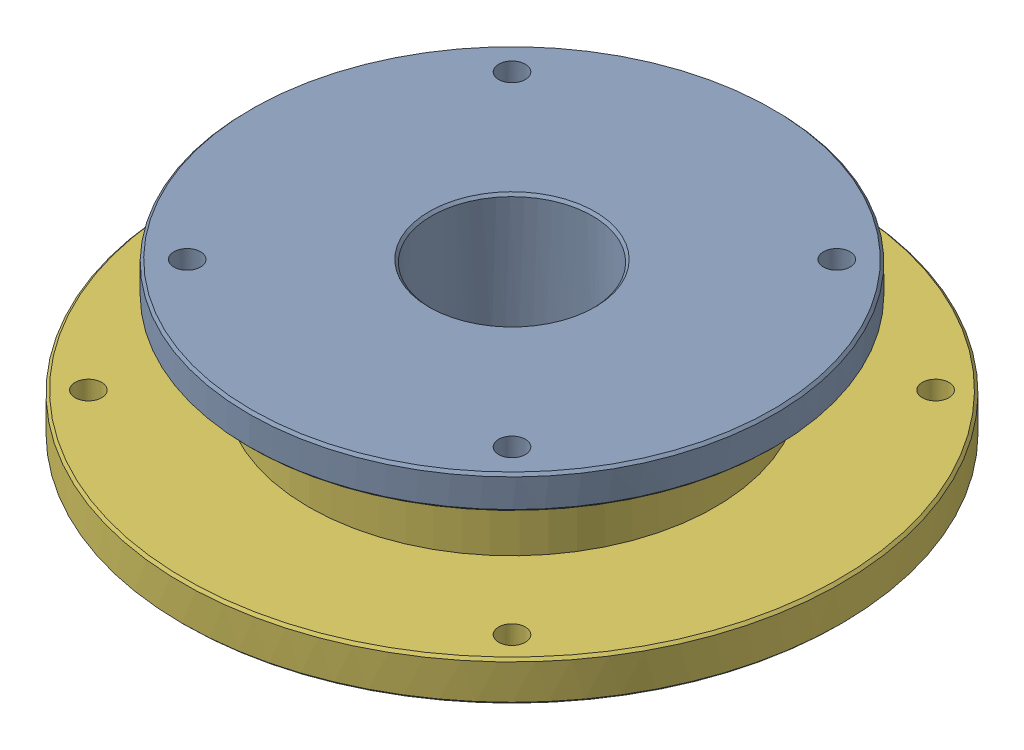
SolidWorks assembly 22212 Bearing Flange Assembly, configuration Default. Lengths in mm.
Overall size (198 46 198).
43 component instances, 6 part files, 6 mates.
Components (placement in the parent):
- 22212 bearing flange-1: 22212 bearing flange [Default] at (0 40.4807 0) size (158 40 158)
- SKF_22212 E_oh-1: SKF_22212 E_oh [Default] at (0 6 0) x (0 1 0) z (-0.933971 0 -0.357349) size (28 110 110)
  - SKF_22212 E_ir_oh-1: SKF_22212 E_ir_oh [Default] at origin size (28 75.82 75.82)
  - SKF_22212 E_or_oh-1: SKF_22212 E_or_oh [Default] at origin size (28 110 110)
  - SKF_22212 E_r1_oh-1: SKF_22212 E_r1_oh [Default] at origin size (11.89 13.47 12.6)
  - SKF_22212 E_r2_oh-1: SKF_22212 E_r2_oh [Default] at origin size (11.89 13.47 12.6)
  - SKF_22212 E_r1_oh-2: SKF_22212 E_r1_oh [Default] x (1 0 0) z (0 -0.324699 0.945817) size (11.89 13.47 12.6)
  - SKF_22212 E_r2_oh-2: SKF_22212 E_r2_oh [Default] x (1 0 0) z (0 -0.324699 0.945817) size (11.89 13.47 12.6)
  - SKF_22212 E_r1_oh-3: SKF_22212 E_r1_oh [Default] x (1 0 0) z (0 -0.614213 0.789141) size (11.89 13.47 12.6)
  - SKF_22212 E_r2_oh-3: SKF_22212 E_r2_oh [Default] x (1 0 0) z (0 -0.614213 0.789141) size (11.89 13.47 12.6)
  - SKF_22212 E_r1_oh-4: SKF_22212 E_r1_oh [Default] x (1 0 0) z (0 -0.837166 0.546948) size (11.89 13.47 12.6)
  - SKF_22212 E_r2_oh-4: SKF_22212 E_r2_oh [Default] x (1 0 0) z (0 -0.837166 0.546948) size (11.89 13.47 12.6)
  - SKF_22212 E_r1_oh-5: SKF_22212 E_r1_oh [Default] x (1 0 0) z (0 -0.9694 0.245485) size (11.89 13.47 12.6)
  - SKF_22212 E_r2_oh-5: SKF_22212 E_r2_oh [Default] x (1 0 0) z (0 -0.9694 0.245485) size (11.89 13.47 12.6)
  - SKF_22212 E_r1_oh-6: SKF_22212 E_r1_oh [Default] x (1 0 0) z (0 -0.996584 -0.082579) size (11.89 13.47 12.6)
  - SKF_22212 E_r2_oh-6: SKF_22212 E_r2_oh [Default] x (1 0 0) z (0 -0.996584 -0.082579) size (11.89 13.47 12.6)
  - SKF_22212 E_r1_oh-7: SKF_22212 E_r1_oh [Default] x (1 0 0) z (0 -0.915773 -0.401695) size (11.89 13.47 12.6)
  - SKF_22212 E_r2_oh-7: SKF_22212 E_r2_oh [Default] x (1 0 0) z (0 -0.915773 -0.401695) size (11.89 13.47 12.6)
  - SKF_22212 E_r1_oh-8: SKF_22212 E_r1_oh [Default] x (1 0 0) z (0 -0.735724 -0.677282) size (11.89 13.47 12.6)
  - SKF_22212 E_r2_oh-8: SKF_22212 E_r2_oh [Default] x (1 0 0) z (0 -0.735724 -0.677282) size (11.89 13.47 12.6)
  - SKF_22212 E_r1_oh-9: SKF_22212 E_r1_oh [Default] x (1 0 0) z (0 -0.475947 -0.879474) size (11.89 13.47 12.6)
  - SKF_22212 E_r2_oh-9: SKF_22212 E_r2_oh [Default] x (1 0 0) z (0 -0.475947 -0.879474) size (11.89 13.47 12.6)
  - SKF_22212 E_r1_oh-10: SKF_22212 E_r1_oh [Default] x (1 0 0) z (0 -0.164595 -0.986361) size (11.89 13.47 12.6)
  - SKF_22212 E_r2_oh-10: SKF_22212 E_r2_oh [Default] x (1 0 0) z (0 -0.164595 -0.986361) size (11.89 13.47 12.6)
  - SKF_22212 E_r1_oh-11: SKF_22212 E_r1_oh [Default] x (1 0 0) z (0 0.164595 -0.986361) size (11.89 13.47 12.6)
  - SKF_22212 E_r2_oh-11: SKF_22212 E_r2_oh [Default] x (1 0 0) z (0 0.164595 -0.986361) size (11.89 13.47 12.6)
  - SKF_22212 E_r1_oh-12: SKF_22212 E_r1_oh [Default] x (1 0 0) z (0 0.475947 -0.879474) size (11.89 13.47 12.6)
  - SKF_22212 E_r2_oh-12: SKF_22212 E_r2_oh [Default] x (1 0 0) z (0 0.475947 -0.879474) size (11.89 13.47 12.6)
  - SKF_22212 E_r1_oh-13: SKF_22212 E_r1_oh [Default] x (1 0 0) z (0 0.735724 -0.677282) size (11.89 13.47 12.6)
  - SKF_22212 E_r2_oh-13: SKF_22212 E_r2_oh [Default] x (1 0 0) z (0 0.735724 -0.677282) size (11.89 13.47 12.6)
  - SKF_22212 E_r1_oh-14: SKF_22212 E_r1_oh [Default] x (1 0 0) z (0 0.915773 -0.401695) size (11.89 13.47 12.6)
  - SKF_22212 E_r2_oh-14: SKF_22212 E_r2_oh [Default] x (1 0 0) z (0 0.915773 -0.401695) size (11.89 13.47 12.6)
  - SKF_22212 E_r1_oh-15: SKF_22212 E_r1_oh [Default] x (1 0 0) z (0 0.996584 -0.082579) size (11.89 13.47 12.6)
  - SKF_22212 E_r2_oh-15: SKF_22212 E_r2_oh [Default] x (1 0 0) z (0 0.996584 -0.082579) size (11.89 13.47 12.6)
  - SKF_22212 E_r1_oh-16: SKF_22212 E_r1_oh [Default] x (1 0 0) z (0 0.9694 0.245485) size (11.89 13.47 12.6)
  - SKF_22212 E_r2_oh-16: SKF_22212 E_r2_oh [Default] x (1 0 0) z (0 0.9694 0.245485) size (11.89 13.47 12.6)
  - SKF_22212 E_r1_oh-17: SKF_22212 E_r1_oh [Default] x (1 0 0) z (0 0.837166 0.546948) size (11.89 13.47 12.6)
  - SKF_22212 E_r2_oh-17: SKF_22212 E_r2_oh [Default] x (1 0 0) z (0 0.837166 0.546948) size (11.89 13.47 12.6)
  - SKF_22212 E_r1_oh-18: SKF_22212 E_r1_oh [Default] x (1 0 0) z (0 0.614213 0.789141) size (11.89 13.47 12.6)
  - SKF_22212 E_r2_oh-18: SKF_22212 E_r2_oh [Default] x (1 0 0) z (0 0.614213 0.789141) size (11.89 13.47 12.6)
  - SKF_22212 E_r1_oh-19: SKF_22212 E_r1_oh [Default] x (1 0 0) z (0 0.324699 0.945817) size (11.89 13.47 12.6)
  - SKF_22212 E_r2_oh-19: SKF_22212 E_r2_oh [Default] x (1 0 0) z (0 0.324699 0.945817) size (11.89 13.47 12.6)
- 22212 bearing bottom flange-1: 22212 bearing bottom flange [Default] at origin size (198 34 198)
Mates (geometry in assembly coordinates):
- Concentric1: concentric anti-aligned: cylinder of mat bich bac dan 22212-1 through (0 40.4807 0) axis (0 1 0) radius 30; cylinder of SKF_22212 E-1/SKF_22212 E_ir-1 through (0 34 0) axis (0 -1 0) radius 30
- Coincident1: coincident anti-aligned: plane of mat bich bac dan 22212-1 through (-30 34 0) normal (0 -1 0); plane of SKF_22212 E-1/SKF_22212 E_ir-1 through (11.2565 34 -29.4201) normal (0 1 0)
- Concentric2: concentric aligned: cylinder of SKF_22212 E-1/SKF_22212 E_or-1 through (0 34 0) axis (0 -1 0) radius 55; cylinder of mat bich bac dan 22212 duoi-1 through (0 0 0) axis (0 -1 0) radius 55
- Coincident2: coincident anti-aligned: plane of SKF_22212 E-1/SKF_22212 E_or-1 through (19.1182 6 -49.9674) normal (0 -1 0); plane of mat bich bac dan 22212 duoi-1 through (-50 6 0) normal (0 1 0)
- Coincident3: coordinate: unknown of mat bich bac dan 22212 duoi-1
- Coincident4: coincident aligned: plane of mat bich bac dan 22212-1 through (0 40.4807 0) normal (0 0 1); plane of mat bich bac dan 22212 duoi-1 through (0 0 0) normal (0 0 1)
